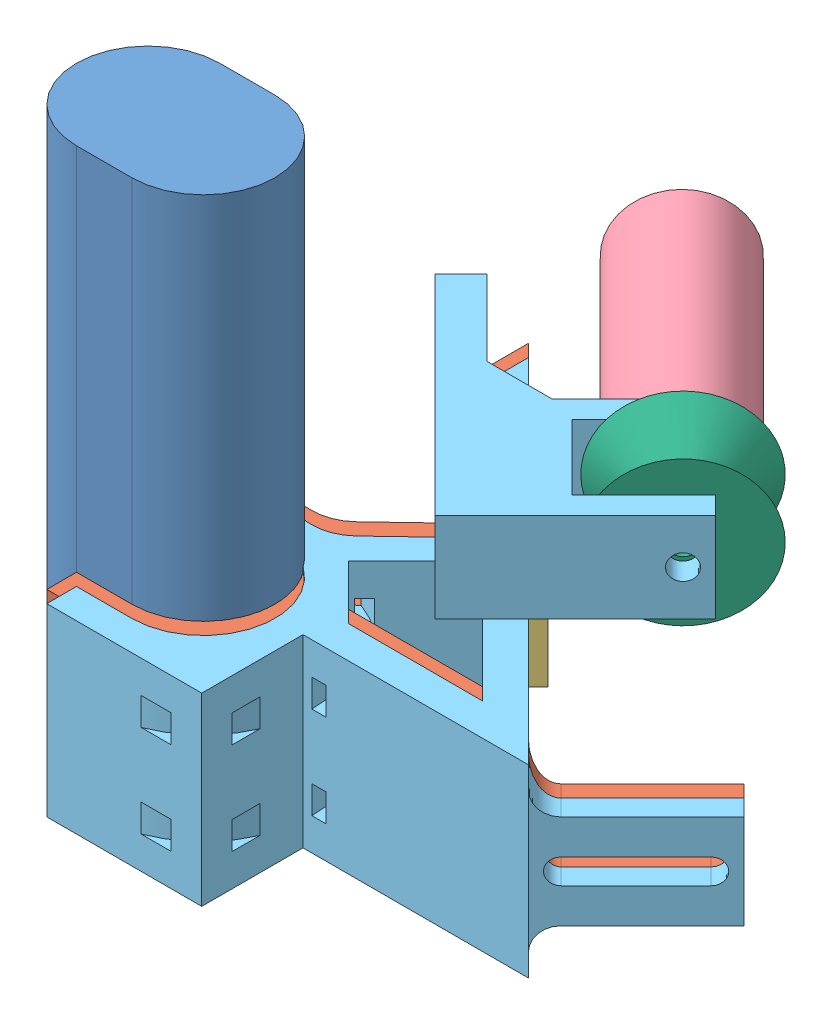
SolidWorks assembly cableDrivenAss, configuration Default. Lengths in mm.
Overall size (312.75 120 257.04).
7 component instances, 7 part files, 12 mates.
Components (placement in the parent):
- post-1: post [Default] at (25.0134 6.7287 96.5918) size (43 120 31)
- Smaller SecondSupport-1: Smaller SecondSupport [Default] at (25.0134 26.7287 96.5918) size (298.83 40 253.53)
- braket-1: braket [Default] at (51.545 26.7287 40.7559) x (0.707107 0 0.707107) z (0 1 0) size (34 36.5 26)
- threaded_cable_retractor-1: threaded_cable_retractor [Default] at (59.3232 26.7287 15.3) x (0.090497 -0.991776 -0.090497) z (-0.701292 -0.127982 0.701292) size (35 148 35) (hidden)
- DC MOTOR-1: DC MOTOR [Default] at (11.2399 26.7287 -32.7832) x (0.605351 -0.516817 -0.605351) z (-0.365445 -0.856096 0.365445) size (25 76 25)
- With wire directionalSmaller SecondSupport-1: With wire directionalSmaller SecondSupport [Default] at (28.5268 27.5729 100.1052) size (298.83 72.25 253.53)
- pulley-1: pulley [Default] at (95.7429 70.1082 51.4555) x (0.707107 0 0.707107) z (-0.68364 -0.255486 0.68364) size (18 31.31 31.31)
Mates (geometry in assembly coordinates):
- Concentric1: concentric anti-aligned: cylinder of post-1 through (37.0134 126.7287 96.5918) axis (0 -1 0) radius 15.5; cylinder of SecondSupport-1 through (37.0134 6.7287 96.5918) axis (0 1 0) radius 15.5
- Coincident1: coincident aligned: plane of post-1 through (37.0134 6.7287 96.5918) normal (0 -1 0); plane of SecondSupport-1 through (25.0134 6.7287 96.5918) normal (0 -1 0)
- Coincident2: coincident anti-aligned: plane of SecondSupport-1 through (107.381 6.7287 96.5918) normal (0.707107 0 -0.707107); plane of braket-1 through (51.545 26.7287 40.7559) normal (-0.707107 0 0.707107)
- Parallel1: parallel aligned: plane of SecondSupport-1 through (25.0134 46.7287 96.5918) normal (0 1 0); plane of braket-1 through (42.7062 39.7287 27.6744) normal (0 1 0)
- Coincident4: coincident anti-aligned: line of SecondSupport-1 through (31.0134 26.7287 20.2243) axis (0.707107 0 0.707107); line of braket-1 through (62.5052 26.7287 51.716) axis (-0.707107 0 -0.707107)
- Concentric4: concentric aligned: cylinder of braket-1 through (80.89 26.7287 36.8668) axis (-0.707107 0 -0.707107) radius 4; cylinder of threaded_cable_retractor-1 through (160.4395 26.7287 116.4163) axis (-0.707107 0 -0.707107) radius 15
- Coincident5: coincident anti-aligned: plane of braket-1 through (68.5156 13.7287 6.1076) normal (0.707107 0 0.707107); plane of threaded_cable_retractor-1 through (59.3232 26.7287 15.3) normal (-0.707107 0 -0.707107)
- Parallel4: parallel aligned: plane of post-1 through (25.0134 126.7287 112.0918) normal (0 0 1); plane of SecondSupport-1 through (58.5764 101.9674 118.5283) normal (0 0 1)
- Coincident6: coincident anti-aligned: plane of braket-1 through (42.7062 13.7287 27.6744) normal (-0.707107 0 -0.707107); plane of DC MOTOR-1 through (57.2019 26.7287 13.1787) normal (0.707107 0 0.707107)
- Concentric5: concentric aligned: cylinder of braket-1 through (80.89 26.7287 36.8668) axis (-0.707107 0 -0.707107) radius 4; cylinder of DC MOTOR-1 through (64.9801 26.7287 20.9569) axis (-0.707107 0 -0.707107) radius 2
- Coincident7: coincident anti-aligned: plane of Smaller SecondSupport-1 through (60.3687 -3.2713 58.5078) normal (-0.707107 0 0.707107); plane of With wire directionalSmaller SecondSupport-1 through (65.2465 27.5729 63.3855) normal (0.707107 0 -0.707107)
- Concentric6: concentric aligned: cylinder of With wire directionalSmaller SecondSupport-1 through (81.3036 70.1082 37.0162) axis (0.707107 0 0.707107) radius 2.7; cylinder of pulley-1 through (95.7429 70.1082 51.4555) axis (0.707107 0 0.707107) radius 2.7
